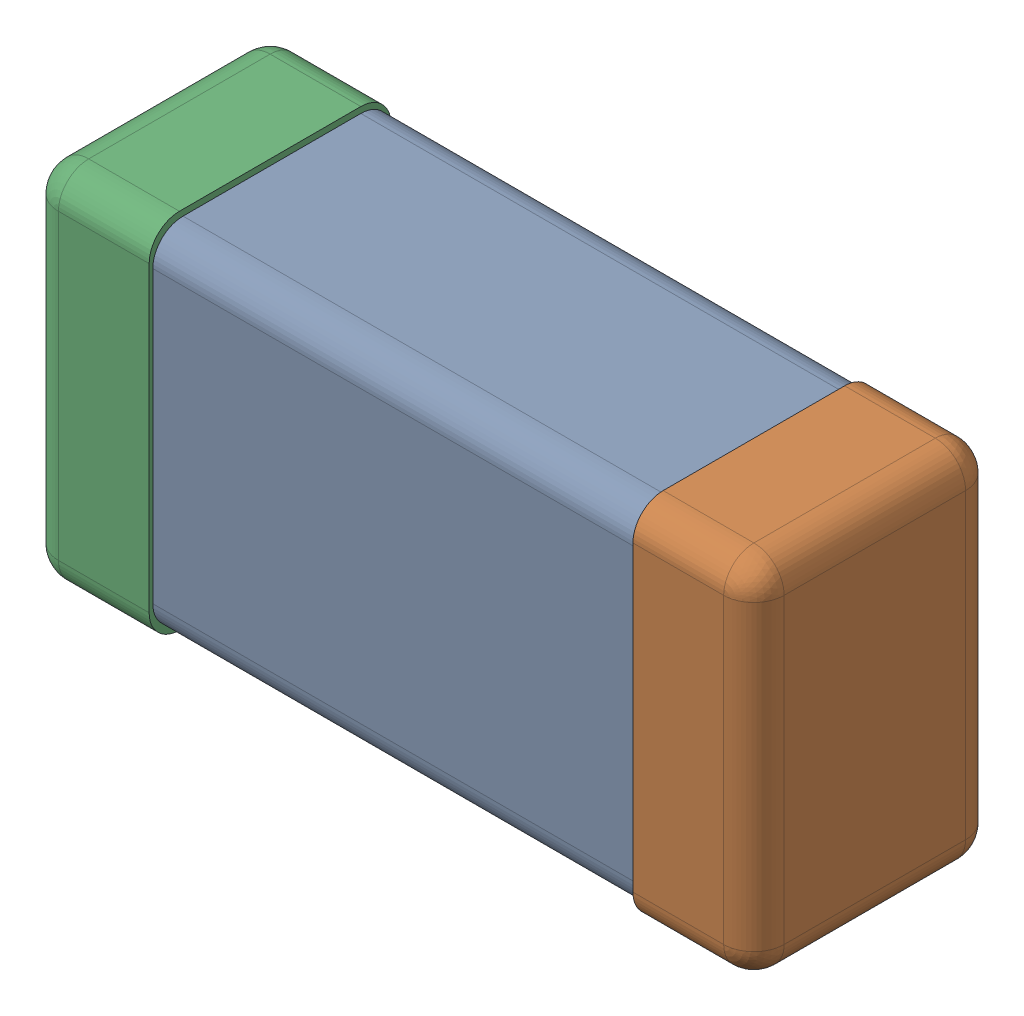
SolidWorks assembly C0201_020_10, configuration Standard. Lengths in mm.
Overall size (0.6 0.3 0.2).
4 component instances, 3 part files, 0 mates.
Components (placement in the parent):
- C0201_020_11-1: C0201_020_11 [Standard] at origin size (0.6 0.3 0.2)
  - Part 3_2-1: Part 3_2 [Standard] at (0 0 -7.3015) size (0.5 0.29 0.2)
  - Part 2_2-1: Part 2_2 [Standard] at (0 0 -7.3) size (0.1 0.3 0.2)
  - Part 1_2-1: Part 1_2 [Standard] at (0 0 -7.3) size (0.1 0.3 0.2)
